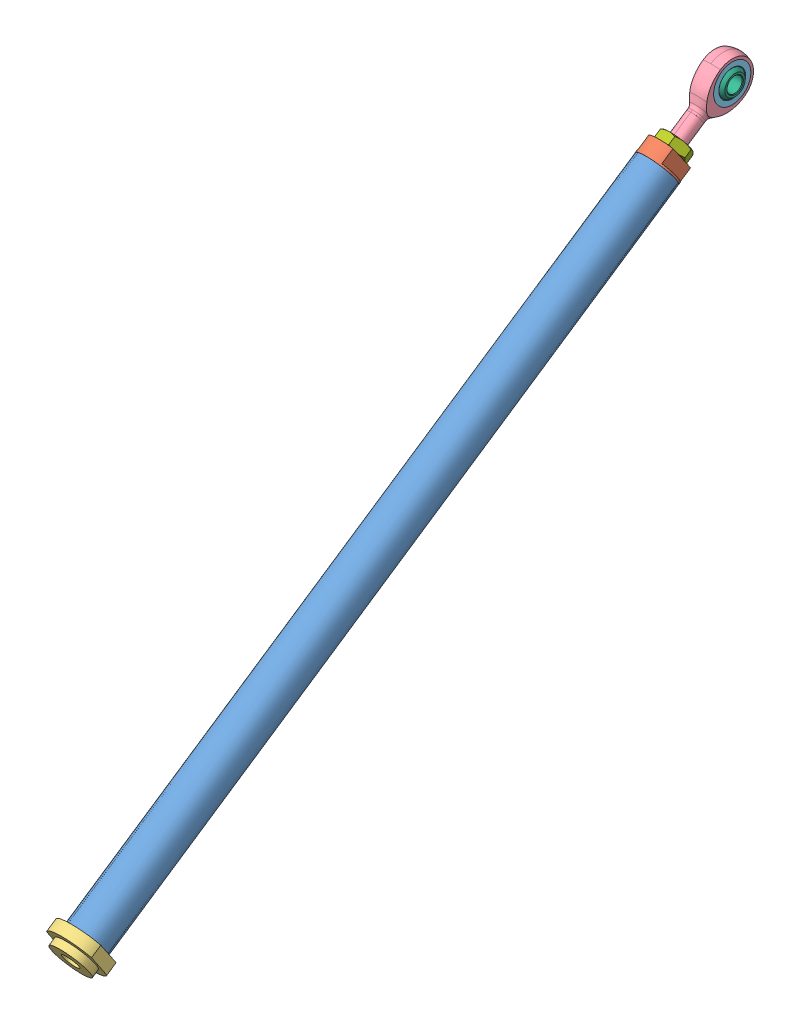
SolidWorks assembly 24-SU-14-000, configuration Default. Lengths in mm.
Overall size (20.31 205.96 292.01).
9 component instances, 8 part files, 10 mates.
Components (placement in the parent):
- 24-SU-00-001-1: 24-SU-00-001 [Default<As Machined>] at origin (suppressed, hidden)
- 24-SU-14-001-1: 24-SU-14-001 [Default<As Machined>] at origin size (15.88 172.39 246.02)
- 24-SU-25-005-1: 24-SU-25-005 [1_4 28] at (0 474.175 162.9402) x (0 -0.557351 0.830277) z (-0.998821 -0.040303 -0.027055) size (21.46 15.88 15.88)
- 24-SU-14-002-1: 24-SU-14-002 [Default] at origin size (18.7 25.51 26.89)
- MM-4T-1: MM-4T [Default] at (0 492.7557 135.2608) x (0 0.830277 0.557351) z (0 0.557351 -0.830277) size (22.24 20.31 52.19)
  - MM-4T Rod End Body-1: MM-4T Rod End Body [Default] at (0 0 -39.6748) size (22.24 20.31 52.19)
  - MM-4T Bearing Bore-1: MM-4T Bearing Bore [Default] at (0 0 -39.6748) size (15.44 7.14 15.44)
  - MM-4T Ball Bearing-1: MM-4T Ball Bearing [Default] at (0 0 -39.6748) size (17.9 17.7 16.29)
- AN4_JamNut-1: AN4_JamNut [93839A805] at (0 478.8202 156.0203) x (-0.802243 -0.495673 -0.332737) z (-0.596997 0.666084 0.447131) size (11.11 3.97 12.83)
Mates (geometry in assembly coordinates):
- Coincident2: coordinate: unknown of 23-SU-00-001-1
- Concentric1: concentric aligned: cylinder of 23-SU-14-001-1 through (0 314.9632 400.1155) axis (0 0.557351 -0.830277) radius 6.6929; cylinder of 23-SU-25-005-1 through (0 465.7518 175.4882) axis (0 0.557351 -0.830277) radius 6.6929
- Coincident3: coincident anti-aligned: plane of 23-SU-14-001-1 through (0 474.175 162.9402) normal (0 0.557351 -0.830277); plane of 23-SU-25-005-1 through (0 474.175 162.9402) normal (0 -0.557351 0.830277)
- Concentric2: concentric anti-aligned: cylinder of 23-SU-14-001-1 through (0 314.9632 400.1155) axis (0 0.557351 -0.830277) radius 7.9375; cylinder of MM-4T-1/MM-4T Rod End Body-1 through (0 477.8621 157.4475) axis (0 -0.557351 0.830277) radius 3.175
- Concentric3: concentric: unknown of ?; cylinder of ? through (4.7625 492.7557 135.2608) axis (1 0 0) radius 3.175
- Coincident6: coincident anti-aligned: plane of 23-SU-25-005-1 through (0 477.7142 157.6679) normal (0 0.557351 -0.830277); plane of AN4_JamNut-1 through (6.3726 478.3316 158.0823) normal (0 -0.557351 0.830277)
- Concentric4: concentric aligned: cylinder of 23-SU-25-005-1 through (0 477.7142 157.6679) axis (0 -0.557351 0.830277) radius 7.9375; cylinder of AN4_JamNut-1 through (0 477.7142 157.6679) axis (0 -0.557351 0.830277) radius 2.7051
- Coincident8: coordinate: unknown of 23-SU-14-002-1
- Parallel1: parallel anti-aligned: plane of MM-4T-1/MM-4T Rod End Body-1 through (-3.5687 500.6641 140.5696) normal (1 0 0)
- Parallel2: parallel anti-aligned: plane of MM-4T-1/MM-4T Rod End Body-1 through (-3.5687 500.6641 140.5696) normal (1 0 0)
